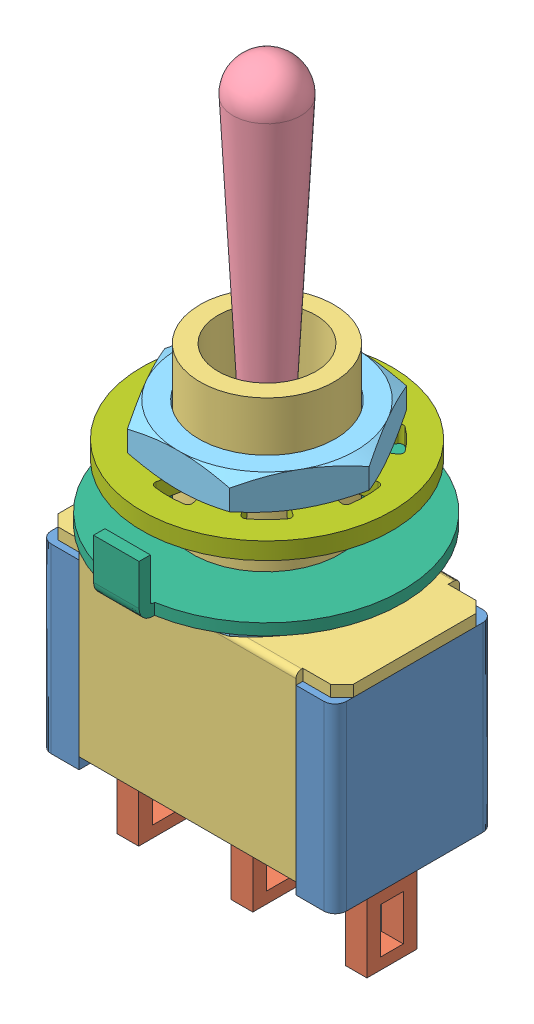
SolidWorks assembly SPDT Toggle Switch, configuration Default. Lengths in mm.
Overall size (13 31.9 12.6).
10 component instances, 7 part files, 0 mates.
Components (placement in the parent):
- SPDT Toggle Switch Base-1: SPDT Toggle Switch Base [Default] at (-12.3077 3.8112 0) size (13 8 7)
- SPDT Toggle Switch Pin-1: SPDT Toggle Switch Pin [Default] at (-5.8077 -0.1888 0) x (1 0 0) z (0 -1 0) size (0.95 2.2 4)
- SPDT Toggle Switch Pin-2: SPDT Toggle Switch Pin [Default] at (-0.7827 -0.1888 0) x (1 0 0) z (0 -1 0) size (0.95 2.2 4)
- SPDT Toggle Switch Pin-3: SPDT Toggle Switch Pin [Default] at (4.2423 -0.1888 0) x (1 0 0) z (0 -1 0) size (0.95 2.2 4)
- SPDT Toggle Switch Treaded Tube-1: SPDT Toggle Switch Treaded Tube [Default] at (-18.8077 7.8112 0) x (-1 0 0) z (0 1 0) size (13 7.2 16.4)
- Toggle Switch-1: Toggle Switch [Default] at (-12.3077 12.4185 3.4998) x (1 0 0) z (0 -0.000203 1) size (3 16.79 3)
- M6x0.5 Hex Nut-1: M6x0.5 Hex Nut [Default] at (-12.3077 9.8112 3.5) x (1 0 0) z (0 -1 0) size (9 7.79 1.5)
- M6x0.5 Hex Nut-2: M6x0.5 Hex Nut [Default] at (-12.3077 13.0612 3.5) x (1 0 0) z (0 1 0) size (9 7.79 1.5)
- SPDT Toggle Switch Anti-Rotation Washer-1: SPDT Toggle Switch Anti-Rotation Washer [Default] at (-12.3077 9.8112 3.5349) x (-1 0 0) z (0 1 0) size (12 12.6 2.4)
- AS 1969 (Internal Tooth Lock Washer Type A) M6-1: AS 1969 (Internal Tooth Lock Washer Type A) M6 [Default] at (-12.3077 13.0612 3.5) x (0 -1 0) z (0 0 1) size (0.75 11 11)
